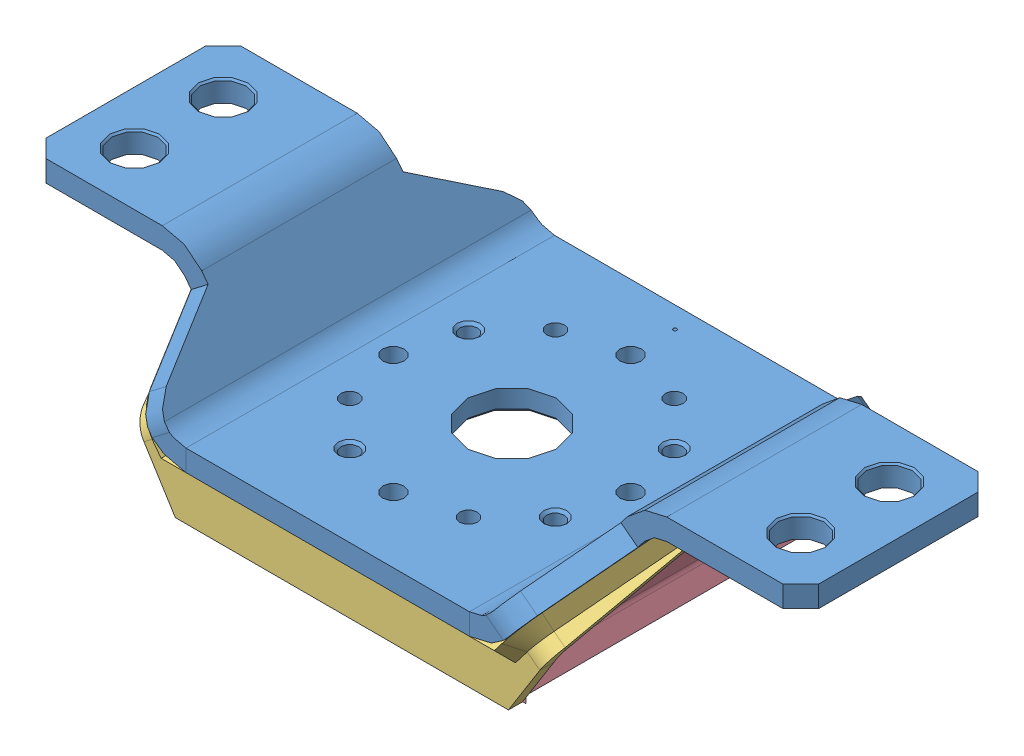
SolidWorks assembly Кронштейн 2х тензодатчиков сварка в1, configuration По умолчанию. Lengths in mm.
Overall size (218 125.16 158.79).
5 component instances, 4 part files, 12 mates.
Components (placement in the parent):
- Кронштейн 2х тензодатчиков в3-1: Кронштейн 2х тензодатчиков в3 [По умолчанию] at origin size (218 32.5 104.87)
- Ребро лев кронштейна 2х тензодатчиков в2-1: Ребро лев кронштейна 2х тензодатчиков в2 [с телами сварочных швов] at (0 -6 -44) size (135.34 40.9 37.66)
- Ребро прав кронштейна 2х тензодатчиков в2-1: Ребро прав кронштейна 2х тензодатчиков в2 [с телами сварочных швов] at (10.7647 8.0289 75.6979) x (0.836641 -0.212893 -0.504686) z (0.504686 0.65772 0.559193) size (116.57 71.27 74.27)
- Ребро прижимное кронштейна 2х тензодатчиков-1: Ребро прижимное кронштейна 2х тензодатчиков [Со сварочными швами] at (-41.9164 -22.5 0) x (-1 0 0) z (0 0 -1) size (21.61 33.01 88)
- Ребро прижимное кронштейна 2х тензодатчиков-2: Ребро прижимное кронштейна 2х тензодатчиков [Со сварочными швами] at (41.9164 -22.5 0) size (21.61 33.01 88)
Mates (geometry in assembly coordinates):
- Совпадение1: coincident aligned: plane of Ребро лев кронштейна 2х тензодатчиков в2-1 through (0 -6 -44) normal (1 0 0); plane of assembly through (0 0 0) normal (1 0 0)
- Совпадение2: coincident anti-aligned: plane of Кронштейн 2х тензодатчиков в3-1 through (109 -6 52) normal (0 -1 0); plane of Ребро лев кронштейна 2х тензодатчиков в2-1 through (0 -6 -48) normal (0 1 0)
- Расстояние1: distance = 4 mm aligned: plane of Ребро лев кронштейна 2х тензодатчиков в2-1 through (0 -22.5 -48) normal (0 0 -1); plane of Кронштейн 2х тензодатчиков в3-1 through (0 -6 -52) normal (0 0 -1)
- Совпадение4: coincident anti-aligned: plane of assembly through (0 0 0) normal (1 0 0); plane of Ребро прав кронштейна 2х тензодатчиков в2-1
- Совпадение5: coincident anti-aligned: plane of Кронштейн 2х тензодатчиков в3-1 through (109 -6 52) normal (0 -1 0); plane of Ребро прав кронштейна 2х тензодатчиков в2-1 through (0 -6 44) normal (0 1 0)
- Расстояние2: distance = 4 mm aligned: plane of Кронштейн 2х тензодатчиков в3-1 through (0 -6 52) normal (0 0 1); plane of Ребро прав кронштейна 2х тензодатчиков в2-1 through (0 -22.5 48) normal (0 0 1)
- Совпадение6: coincident anti-aligned: plane of Кронштейн 2х тензодатчиков в3-1 through (-87.2434 46.5712 52) normal (-0.793353 -0.608761 0); plane of Ребро прижимное кронштейна 2х тензодатчиков-1 through (-41.9164 -12.5 44) normal (0.793353 0.608761 0)
- Совпадение7: coincident aligned: plane of Ребро прав кронштейна 2х тензодатчиков в2-1 through (0 -22.5 44) normal (0 -1 0); plane of Ребро прижимное кронштейна 2х тензодатчиков-1 through (-45.9164 -22.5 44) normal (0 -1 0)
- Совпадение8: coincident anti-aligned: plane of Ребро лев кронштейна 2х тензодатчиков в2-1 through (0 -22.5 -44) normal (0 0 1); plane of Ребро прижимное кронштейна 2х тензодатчиков-1 through (-49.9164 -15.2156 -44) normal (0 0 -1)
- Совпадение9: coincident anti-aligned: plane of Ребро прижимное кронштейна 2х тензодатчиков-2; plane of Кронштейн 2х тензодатчиков в3-1 through (87.2434 46.5712 52) normal (0.793353 -0.608761 0)
- Совпадение10: coincident aligned: plane of Ребро прав кронштейна 2х тензодатчиков в2-1 through (0 -22.5 44) normal (0 -1 0); plane of Ребро прижимное кронштейна 2х тензодатчиков-2
- Совпадение11: coincident anti-aligned: plane of Ребро лев кронштейна 2х тензодатчиков в2-1 through (0 -22.5 -44) normal (0 0 1); plane of Ребро прижимное кронштейна 2х тензодатчиков-2 through (46.743 -12.7806 -44) normal (0 0 -1)
